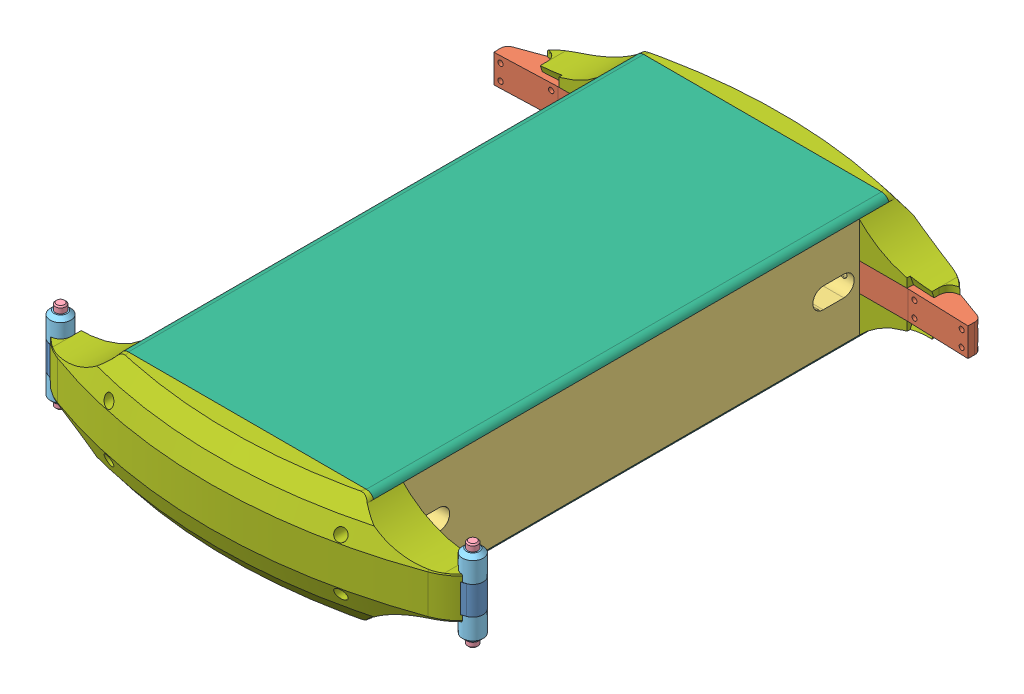
SolidWorks assembly Rahmen, configuration Standard. Lengths in mm.
Overall size (184.13 43.58 229).
14 component instances, 7 part files, 33 mates.
Components (placement in the parent):
- Rahmen-Vorne-1: Rahmen-Vorne [Standard] at (0 0 92.5) size (168 11 24)
- Rahmen-Hinten-3: Rahmen-Hinten [Standard] at (0 0 -92.5) x (-1 0 0) z (0 0 -1) size (184.13 11 24.84)
- Rahmen-Seite-1: Rahmen-Seite [Standard] at (-45 0 0) x (0 0 -1) z (1 0 0) size (200 39 8)
- Rahmen-Seite-2: Rahmen-Seite [Standard] at (45 0 0) x (0 0 1) z (-1 0 0) size (200 39 8)
- Achse 4mm-1: Achse 4mm [L=35] at (-80 0 92.5) x (0 -1 0) z (0 0 1) size (35 4 4)
- Rad-Abstandshalter-1: Rad-Abstandshalter [Standard] at (-80 5.5 92.5) size (8 9.5 8)
- Rad-Abstandshalter-4: Rad-Abstandshalter [Standard] at (-80 -5.5 92.5) x (-1 0 0) z (0 0 1) size (8 9.5 8)
- Rahmen-Deckel-1: Rahmen-Deckel [Standard] at (0 -20 0) x (-1 0 0) z (0 0 1) size (98 3 200)
- Rad-Abstandshalter-24: Rad-Abstandshalter [Standard] at (80 -5.5 92.5) x (1 0 0) z (0 0 -1) size (8 9.5 8)
- Achse 4mm-13: Achse 4mm [L=35] at (80 0 92.5) x (0 -1 0) z (0 0 -1) size (35 4 4)
- Rad-Abstandshalter-25: Rad-Abstandshalter [Standard] at (80 5.5 92.5) x (-1 0 0) z (0 0 -1) size (8 9.5 8)
- Rahmen-Deckel-2: Rahmen-Deckel [Standard] at (0 20 0) size (98 3 200)
- Rahmen-Verkleidung-1: Rahmen-Verkleidung [Vorne] at (0 0 92.5) size (160 43.58 26)
- Rahmen-Verkleidung-2: Rahmen-Verkleidung [Hinten] at (0 0 -92.5) x (-1 0 0) z (0 0 -1) size (160 43.58 26)
Mates (geometry in assembly coordinates):
- Deckungsgleich4: coincident aligned: plane of Rahmen-Vorne-1 through (0 0 92.5) normal (0 1 0); plane of assembly through (0 0 0) normal (0 1 0)
- Deckungsgleich6: coincident aligned: plane of Rahmen-Vorne-1 through (0 0 92.5) normal (1 0 0); plane of assembly through (0 0 0) normal (1 0 0)
- Konzentrisch1: concentric anti-aligned: cylinder of Rahmen-Vorne-1 through (-80 5.5 92.5) axis (0 -1 0) radius 2; cylinder of Achse 4mm-1 through (-80 -17.5 92.5) axis (0 1 0) radius 2
- Deckungsgleich7: coincident anti-aligned: plane of Achse 4mm-1; plane of assembly through (0 0 0) normal (0 1 0)
- Konzentrisch3: concentric aligned: cylinder of Achse 4mm-1 through (-80 -17.5 92.5) axis (0 1 0) radius 2; cylinder of Rad-Abstandshalter-1 through (-80 32.713 92.5) axis (0 1 0) radius 2
- Deckungsgleich11: coincident anti-aligned: plane of Rahmen-Vorne-1 through (0 -5.5 92.5) normal (0 -1 0); plane of Rad-Abstandshalter-4 through (-76 -5.5 92.5) normal (0 1 0)
- Deckungsgleich12: coincident anti-aligned: plane of Rahmen-Vorne-1 through (0 5.5 92.5) normal (0 1 0); plane of Rad-Abstandshalter-1 through (-84 5.5 92.5) normal (0 -1 0)
- Konzentrisch4: concentric anti-aligned: cylinder of Achse 4mm-1 through (-80 -17.5 92.5) axis (0 1 0) radius 2; cylinder of Rad-Abstandshalter-4 through (-80 -32.713 92.5) axis (0 -1 0) radius 2
- Deckungsgleich13: coincident aligned: plane of Achse 4mm-1 through (-80 0 92.5) normal (0 0 1); plane of Rad-Abstandshalter-1 through (-80 5.5 92.5) normal (0 0 1)
- Deckungsgleich14: coincident aligned: plane of Achse 4mm-1 through (-80 0 92.5) normal (0 0 1); plane of Rad-Abstandshalter-4 through (-80 -5.5 92.5) normal (0 0 1)
- Parallel1: parallel aligned: plane of Achse 4mm-1 through (-80 0 92.5) normal (0 0 1); plane of assembly through (0 0 0) normal (0 0 1)
- Deckungsgleich18: coincident anti-aligned: plane of Rahmen-Seite-1 through (-45 0 0) normal (0 0 -1); plane of assembly through (0 0 0) normal (0 0 1)
- Deckungsgleich19: coincident aligned: plane of Rahmen-Seite-1; plane of assembly through (0 0 0) normal (0 1 0)
- Deckungsgleich20: coincident anti-aligned: plane of Rahmen-Vorne-1 through (0 5.5 88.5) normal (0 0 -1); plane of Rahmen-Seite-1 through (-49 -5.5 88.5) normal (0 0 1)
- Deckungsgleich21: coincident aligned: plane of Rahmen-Seite-2; plane of assembly through (0 0 0) normal (0 1 0)
- Deckungsgleich22: coincident aligned: plane of Rahmen-Seite-2 through (45 0 0) normal (0 0 1); plane of assembly through (0 0 0) normal (0 0 1)
- Deckungsgleich23: coincident aligned: plane of Rahmen-Hinten-3; plane of assembly through (0 0 0) normal (0 1 0)
- Deckungsgleich24: coincident anti-aligned: plane of Rahmen-Hinten-3 through (0 0 -92.5) normal (-1 0 0); plane of assembly through (0 0 0) normal (1 0 0)
- Deckungsgleich25: coincident anti-aligned: plane of Rahmen-Hinten-3 through (0 5.5 -88.5) normal (0 0 1); plane of Rahmen-Seite-1 through (-49 -5.5 -88.5) normal (0 0 -1)
- Konzentrisch5: concentric aligned: cylinder of Rahmen-Vorne-1 through (-45 0 112.5) axis (0 0 1) radius 1.6; cylinder of Rahmen-Seite-1 through (-45 0 88.5) axis (0 0 1) radius 1.25
- Konzentrisch6: concentric aligned: cylinder of Rahmen-Vorne-1 through (45 0 112.5) axis (0 0 1) radius 1.6; cylinder of Rahmen-Seite-2 through (45 0 88.5) axis (0 0 1) radius 1.25
- Deckungsgleich27: coincident aligned: plane of Rahmen-Hinten-3 through (0 0 -92.5) normal (-1 0 0); plane of Rahmen-Deckel-1
- Deckungsgleich28: coincident aligned: plane of assembly through (0 0 0) normal (0 0 1); plane of Rahmen-Deckel-1 through (0 -20 0) normal (0 0 1)
- Deckungsgleich29: coincident anti-aligned: plane of Rahmen-Seite-1 through (-49 -19.5 100) normal (0 -1 0); plane of Rahmen-Deckel-1 through (0 -19.5 0) normal (0 1 0)
- Deckungsgleich30: coincident aligned: plane of Rahmen-Deckel-2 through (0 20 0) normal (0 0 1); plane of assembly through (0 0 0) normal (0 0 1)
- Deckungsgleich31: coincident aligned: plane of Rahmen-Deckel-2 through (0 20 0) normal (1 0 0); plane of assembly through (0 0 0) normal (1 0 0)
- Deckungsgleich32: coincident anti-aligned: plane of Rahmen-Seite-2 through (49 19.5 -100) normal (0 1 0); plane of Rahmen-Deckel-2 through (0 19.5 0) normal (0 -1 0)
- Konzentrisch7: concentric aligned: cylinder of Rahmen-Vorne-1 through (0 5.5 -95.895) axis (0 -1 0) radius 208.395; cylinder of Rahmen-Verkleidung-1 through (0 5.5 -95.895) axis (0 -1 0) radius 208.395
- Deckungsgleich33: coincident aligned: plane of Rahmen-Verkleidung-1 through (0 0 92.5) normal (0 1 0); plane of assembly through (0 0 0) normal (0 1 0)
- Deckungsgleich34: coincident aligned: plane of Rahmen-Verkleidung-1 through (0 0 92.5) normal (1 0 0); plane of assembly through (0 0 0) normal (1 0 0)
- Konzentrisch8: concentric aligned: cylinder of Rahmen-Hinten-3 through (0 5.5 95.895) axis (0 -1 0) radius 208.395; cylinder of Rahmen-Verkleidung-2 through (0 5.5 95.895) axis (0 -1 0) radius 208.395
- Deckungsgleich35: coincident anti-aligned: plane of Rahmen-Verkleidung-2 through (0 0 -92.5) normal (-1 0 0); plane of assembly through (0 0 0) normal (1 0 0)
- Deckungsgleich36: coincident aligned: plane of Rahmen-Verkleidung-2; plane of assembly through (0 0 0) normal (0 1 0)
